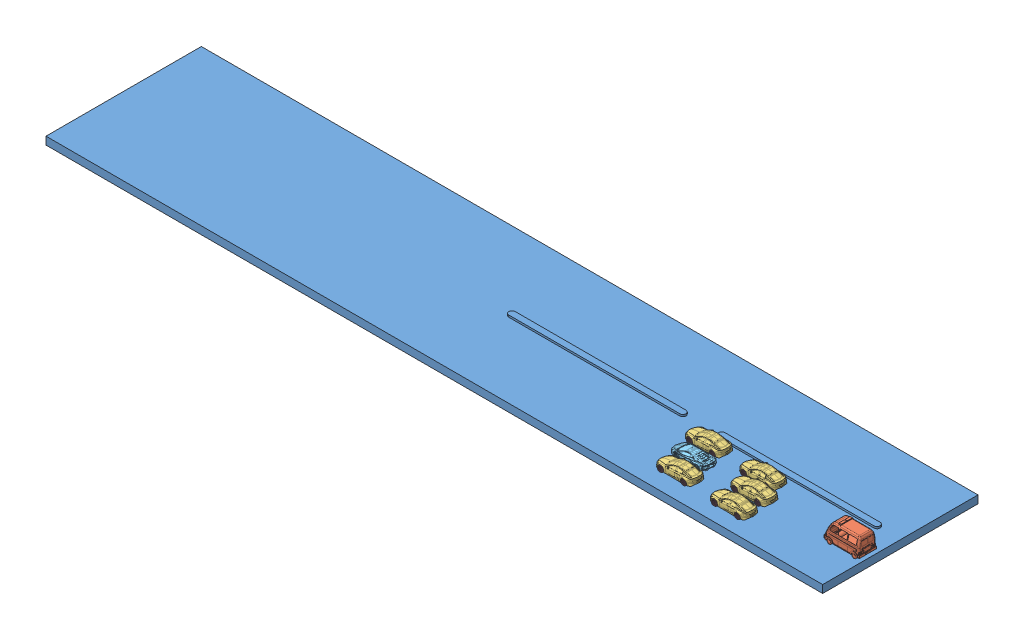
SolidWorks assembly ass, configuration Default. Lengths in mm.
Overall size (100000 3618.01 21294).
33 component instances, 5 part files, 22 mates.
Components (placement in the parent):
- road-2: road [Default] at (36118.1422 49806.7497 79012.69) size (100000 1250 20000)
- AMBULANCE-1: AMBULANCE [Varsayılan] at (85832.8495 50106.7497 84081.5226) x (-1 0 0) z (0 0 -1) size (4597.97 2618.01 2300)
- Model S Assembly-1: Model S Assembly [Default] at (63387.7317 50580.5825 80950.5749) x (0 0 1) z (-1 0.000316 0) size (5212.42 1655.86 5010.67)
  - Tesla Model S Body-1: Tesla Model S Body [Default] at (-4.3435 685.841 -370.7377) size (2261.89 1291.55 4996.29)
  - Model S Wheels-1: Model S Wheels [Default] at (-135.9279 -2465.0421 940.7452) x (0.983255 0 -0.182236) z (-0.025709 0.989999 -0.138715) size (301.46 727.68 727.68)
  - Model S Wheels-2: Model S Wheels [Default] at (1.6901 802.4686 -3246.3873) x (1 0 0) z (0 -0.080454 0.996758) size (301.46 727.68 727.68)
  - Model S Wheels-3: Model S Wheels [Default] at (-7.6652 1704.9145 -2000.2571) x (-1 0 0) z (0 -0.973095 -0.230404) size (301.46 727.68 727.68)
  - Model S Wheels-4: Model S Wheels [Default] at (28.5839 -263.9248 -637.1748) x (-1 0 0) z (0 -0.539062 0.842266) size (301.46 727.68 727.68)
- Lamborghini aventador ultimae-1: Lamborghini aventador ultimae [Default] at (63945.4948 49812.7917 83447.9019) x (-0.023856 0.019196 0.999531) z (0.01142 0.999756 -0.018928) size (3720.31 4970.76 2284.55)
- Model S Assembly-2: Model S Assembly [Default] at (64688.0101 50547.8355 85956.204) x (0 0 1) z (-1 0.000316 0) size (5212.42 1655.86 5010.67)
  - Tesla Model S Body-1: Tesla Model S Body [Default] at (-4.3435 685.841 -370.7377) size (2261.89 1291.55 4996.29)
  - Model S Wheels-1: Model S Wheels [Default] at (-135.9279 -2465.0421 940.7452) x (0.983255 0 -0.182236) z (-0.025709 0.989999 -0.138715) size (301.46 727.68 727.68)
  - Model S Wheels-2: Model S Wheels [Default] at (1.6901 802.4686 -3246.3873) x (1 0 0) z (0 -0.080454 0.996758) size (301.46 727.68 727.68)
  - Model S Wheels-3: Model S Wheels [Default] at (-7.6652 1704.9145 -2000.2571) x (-1 0 0) z (0 -0.973095 -0.230404) size (301.46 727.68 727.68)
  - Model S Wheels-4: Model S Wheels [Default] at (28.5839 -263.9248 -637.1748) x (-1 0 0) z (0 -0.539062 0.842266) size (301.46 727.68 727.68)
- Model S Assembly-3: Model S Assembly [Default] at (70542.6067 50580.5825 81119.0341) x (0 0 1) z (-1 0.000316 0) size (5212.42 1655.86 5010.67)
  - Tesla Model S Body-1: Tesla Model S Body [Default] at (-4.3435 685.841 -370.7377) size (2261.89 1291.55 4996.29)
  - Model S Wheels-1: Model S Wheels [Default] at (-135.9279 -2465.0421 940.7452) x (0.983255 0 -0.182236) z (-0.025709 0.989999 -0.138715) size (301.46 727.68 727.68)
  - Model S Wheels-2: Model S Wheels [Default] at (1.6901 802.4686 -3246.3873) x (1 0 0) z (0 -0.080454 0.996758) size (301.46 727.68 727.68)
  - Model S Wheels-3: Model S Wheels [Default] at (-7.6652 1704.9145 -2000.2571) x (-1 0 0) z (0 -0.973095 -0.230404) size (301.46 727.68 727.68)
  - Model S Wheels-4: Model S Wheels [Default] at (28.5839 -263.9248 -637.1748) x (-1 0 0) z (0 -0.539062 0.842266) size (301.46 727.68 727.68)
- Model S Assembly-4: Model S Assembly [Default] at (71945.6504 50580.5825 86286.5081) x (0 0 1) z (-1 0.000316 0) size (5212.42 1655.86 5010.67)
  - Tesla Model S Body-1: Tesla Model S Body [Default] at (-4.3435 685.841 -370.7377) size (2261.89 1291.55 4996.29)
  - Model S Wheels-1: Model S Wheels [Default] at (-135.9279 -2465.0421 940.7452) x (0.983255 0 -0.182236) z (-0.025709 0.989999 -0.138715) size (301.46 727.68 727.68)
  - Model S Wheels-2: Model S Wheels [Default] at (1.6901 802.4686 -3246.3873) x (1 0 0) z (0 -0.080454 0.996758) size (301.46 727.68 727.68)
  - Model S Wheels-3: Model S Wheels [Default] at (-7.6652 1704.9145 -2000.2571) x (-1 0 0) z (0 -0.973095 -0.230404) size (301.46 727.68 727.68)
  - Model S Wheels-4: Model S Wheels [Default] at (28.5839 -263.9248 -637.1748) x (-1 0 0) z (0 -0.539062 0.842266) size (301.46 727.68 727.68)
- Model S Assembly-6: Model S Assembly [Default] at (71754.658 50583.9899 83486.8049) x (0 0 1) z (-0.999998 -0.001871 0) size (5212.42 1655.86 5010.67)
  - Tesla Model S Body-1: Tesla Model S Body [Default] at (-4.3435 685.841 -370.7377) size (2261.89 1291.55 4996.29)
  - Model S Wheels-1: Model S Wheels [Default] at (-135.9279 -2465.0421 940.7452) x (0.983255 0 -0.182236) z (-0.025709 0.989999 -0.138715) size (301.46 727.68 727.68)
  - Model S Wheels-2: Model S Wheels [Default] at (1.6901 802.4686 -3246.3873) x (1 0 0) z (0 -0.080454 0.996758) size (301.46 727.68 727.68)
  - Model S Wheels-3: Model S Wheels [Default] at (-7.6652 1704.9145 -2000.2571) x (-1 0 0) z (0 -0.973095 -0.230404) size (301.46 727.68 727.68)
  - Model S Wheels-4: Model S Wheels [Default] at (28.5839 -263.9248 -637.1748) x (-1 0 0) z (0 -0.539062 0.842266) size (301.46 727.68 727.68)
Mates (geometry in assembly coordinates):
- Tangent1: tangent anti-aligned: plane of road-2 through (36118.1422 49806.7497 79012.69) normal (0 1 0); cylinder of AMBULANCE-1 through (82032.8495 50106.7497 83901.5226) axis (0 0 1) radius 300
- Tangent2: tangent anti-aligned: plane of road-2 through (36118.1422 49806.7497 79012.69) normal (0 1 0); cylinder of Model S Assembly-1/Model S Wheels-2 through (64796.9967 50170.5908 81927.69) axis (0 0 -1) radius 363.8411
- Tangent5: tangent anti-aligned: plane of road-2 through (36118.1422 49806.7497 79012.69) normal (0 1 0); cylinder of AMBULANCE-1 through (85232.8495 50106.7497 82061.5226) axis (0 0 -1) radius 300
- Tangent6: tangent anti-aligned: plane of road-2 through (36118.1422 49806.7497 79012.69) normal (0 1 0); cylinder of Model S Assembly-1/Model S Wheels-4 through (61828.8616 50170.5908 80003.7339) axis (0 0 1) radius 363.8411
- Tangent14: tangent anti-aligned: plane of road-2 through (36118.1422 49806.7497 79012.69) normal (0 1 0); cylinder of Lamborghini aventador ultimae-1 through (65313.6327 50162.6934 84464.5751) axis (0.024071 0 -0.99971) radius 355.9437
- Tangent15: tangent anti-aligned: plane of road-2 through (36118.1422 49806.7497 79012.69) normal (0 1 0); cylinder of Lamborghini aventador ultimae-1 through (62661.9028 50137.2592 82459.1027) axis (-0.024071 0 0.99971) radius 330.5095
- Distance1: distance = 2500 mm aligned: plane of road-2 through (83118.1422 50056.7497 79412.69) normal (0 0 1); plane of Model S Assembly-1/Model S Wheels-2 through (64796.9967 50170.5908 81912.69) normal (0 0 1)
- Parallel8: parallel aligned: plane of road-2 through (36118.1422 50056.7497 78612.69) normal (0 0 -1); plane of AMBULANCE-1 through (85232.8495 50106.7497 81831.5226) normal (0 0 -1)
- Tangent16: tangent anti-aligned: plane of road-2 through (36118.1422 49806.7497 79012.69) normal (0 1 0); cylinder of Model S Assembly-3/Model S Wheels-2 through (71951.8717 50170.5908 82096.1491) axis (0 0 -1) radius 363.8411
- Tangent19: tangent anti-aligned: plane of road-2 through (36118.1422 49806.7497 79012.69) normal (0 1 0); cylinder of Model S Assembly-3/Model S Wheels-4 through (68983.7366 50170.5908 80172.193) axis (0 0 1) radius 363.8411
- Parallel9: parallel aligned: plane of road-2 through (83118.1422 50056.7497 79412.69) normal (0 0 1); plane of Model S Assembly-3/Model S Wheels-2 through (71951.8717 50170.5908 82081.1491) normal (0 0 1)
- Tangent20: tangent anti-aligned: plane of road-2 through (36118.1422 49806.7497 79012.69) normal (0 1 0); cylinder of Model S Assembly-6/Model S Wheels-3 through (73168.2692 50170.5908 82503.7148) axis (0 0 1) radius 363.8411
- Tangent21: tangent anti-aligned: plane of road-2 through (36118.1422 49806.7497 79012.69) normal (0 1 0); cylinder of Model S Assembly-4/Model S Wheels-2 through (73354.9154 50170.5908 87263.6231) axis (0 0 -1) radius 363.8411
- Tangent22: tangent anti-aligned: plane of road-2 through (36118.1422 49806.7497 79012.69) normal (0 1 0); cylinder of Model S Assembly-4/Model S Wheels-4 through (70386.7803 50170.5908 85339.667) axis (0 0 1) radius 363.8411
- Tangent23: tangent anti-aligned: plane of road-2 through (36118.1422 49806.7497 79012.69) normal (0 1 0); cylinder of Model S Assembly-6/Model S Wheels-4 through (70196.6881 50170.5908 82539.9639) axis (0 0 1) radius 363.8411
- Parallel10: parallel anti-aligned: plane of road-2 through (83118.1422 50056.7497 79412.69) normal (0 0 1); plane of Model S Assembly-6/Model S Wheels-3 through (73168.2692 50170.5908 82518.7148) normal (0 0 -1)
- Parallel11: parallel aligned: plane of road-2 through (83118.1422 50056.7497 79412.69) normal (0 0 1); plane of Model S Assembly-4/Model S Wheels-2 through (73354.9154 50170.5908 87248.6231) normal (0 0 1)
- Tangent24: tangent anti-aligned: plane of road-2 through (36118.1422 49806.7497 79012.69) normal (0 1 0); cylinder of Model S Assembly-6/Model S Wheels-3 through (75641.0296 50170.5908 82323.4192) axis (0 0 1) radius 363.8411
- Tangent25: tangent anti-aligned: plane of road-2 through (36118.1422 49806.7497 79012.69) normal (0 1 0); cylinder of Model S Assembly-6/Model S Wheels-4 through (72669.4484 50170.5908 82359.6682) axis (0 0 1) radius 363.8411
- Tangent26: tangent anti-aligned: plane of road-2 through (36118.1422 49806.7497 79012.69) normal (0 1 0); cylinder of Model S Assembly-2/Model S Wheels-3 through (66100.7212 50170.5908 84973.1139) axis (0 0 1) radius 363.8411
- Tangent27: tangent anti-aligned: plane of road-2 through (36118.1422 49806.7497 79012.69) normal (0 1 0); cylinder of Model S Assembly-2/Model S Wheels-4 through (63129.1401 50170.5908 85009.363) axis (0 0 1) radius 363.8411
- Tangent28: tangent anti-aligned: plane of road-2 through (36118.1422 49806.7497 79012.69) normal (0 1 0); cylinder of Model S Assembly-2/Model S Wheels-3 through (66100.7212 50170.5908 84973.1139) axis (0 0 1) radius 363.8411
